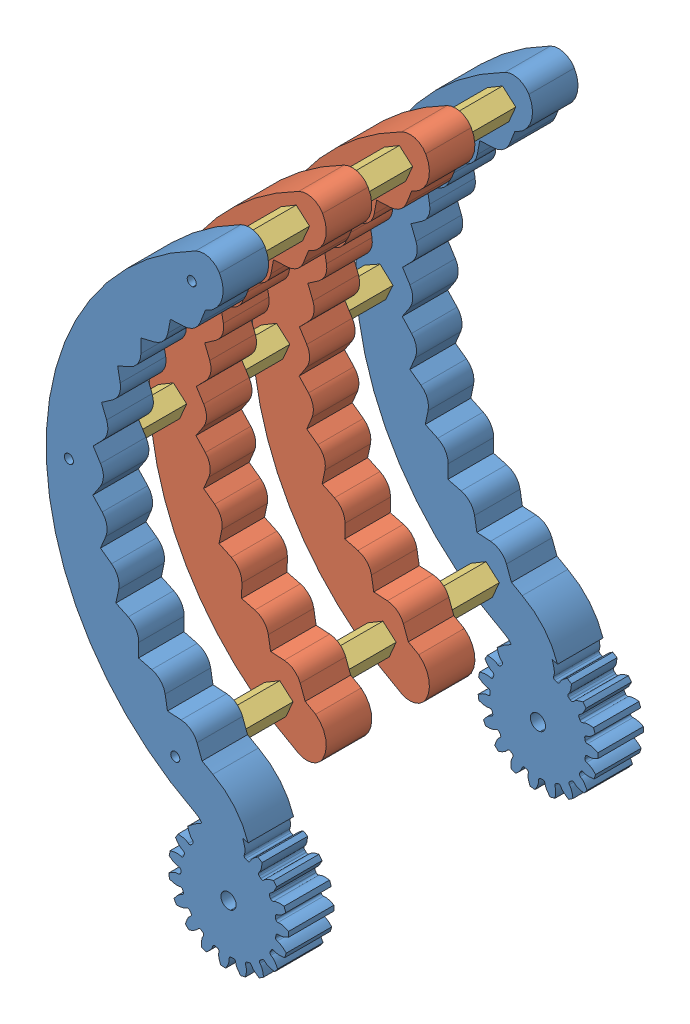
SolidWorks assembly 装配体_右爪子, configuration Default. Lengths in mm.
Overall size (79.93 200.48 117).
13 component instances, 3 part files, 27 mates.
Components (placement in the parent):
- 1_2.右爪子表面_打印两个-1: 1_2.右爪子表面_打印两个 [Varsayılan] at origin size (79.93 200.48 15)
- 1_3.爪子中间_打印四个-1: 1_3.爪子中间_打印四个 [Varsayılan] at (-2.9763 8.2953 -34) size (58.35 161.77 15)
- 2.铜柱连接件-1: 2.铜柱连接件 [Varsayılan] at (-63.7872 8.2778 -21.5) size (9.37 9.17 19)
- 2.铜柱连接件-2: 2.铜柱连接件 [Varsayılan] at (-23.2882 79.2861 -21.5) size (9.37 9.17 19)
- 2.铜柱连接件-3: 2.铜柱连接件 [Varsayılan] at (-23.2882 79.2861 -55.5) size (9.37 9.17 19)
- 2.铜柱连接件-4: 2.铜柱连接件 [Varsayılan] at (-28.7173 -59.225 -21.5) size (9.37 9.17 19)
- 2.铜柱连接件-5: 2.铜柱连接件 [Varsayılan] at (-28.7173 -59.225 -55.5) size (9.37 9.17 19)
- 2.铜柱连接件-6: 2.铜柱连接件 [Varsayılan] at (-23.2882 79.2861 -89.5) size (9.37 9.17 19)
- 2.铜柱连接件-7: 2.铜柱连接件 [Varsayılan] at (-28.7173 -59.225 -89.5) size (9.37 9.17 19)
- 2.铜柱连接件-8: 2.铜柱连接件 [Varsayılan] at (-63.7872 8.2778 -55.5) size (9.37 9.17 19)
- 2.铜柱连接件-9: 2.铜柱连接件 [Varsayılan] at (-63.7872 8.2778 -70.5) x (-0.498458 -0.866914 0) z (0 0 -1) size (9.37 9.17 19)
- 1_3.爪子中间_打印四个-2: 1_3.爪子中间_打印四个 [Varsayılan] at (-2.9763 8.2953 -68) size (58.35 161.77 15)
- 1_2.右爪子表面_打印两个-2: 1_2.右爪子表面_打印两个 [Varsayılan] at (0 0 -102) size (79.93 200.48 15)
Mates (geometry in assembly coordinates):
- 重合1: coincident anti-aligned: plane of 1_2.右爪子表面_打印两个-1 through (-26.0891 71.0659 -2.5) normal (0 0 -1); plane of 2.铜柱连接件-2 through (-23.2882 79.2861 -2.5) normal (0 0 1)
- 同心1: concentric aligned: cylinder of 1_2.右爪子表面_打印两个-1 through (-23.2882 79.2861 -1) axis (0 0 -1) radius 1.5; cylinder of 2.铜柱连接件-2 through (-23.2882 79.2861 -2.5) axis (0 0 -1) radius 2.5
- 重合2: coincident anti-aligned: plane of 1_2.右爪子表面_打印两个-1 through (-26.0891 71.0659 -2.5) normal (0 0 -1); plane of 2.铜柱连接件-1 through (-63.7872 8.2778 -2.5) normal (0 0 1)
- 同心2: concentric aligned: cylinder of 1_2.右爪子表面_打印两个-1 through (-63.7872 8.2778 -1) axis (0 0 -1) radius 1.5; cylinder of 2.铜柱连接件-1 through (-63.7872 8.2778 -2.5) axis (0 0 -1) radius 2.5
- 重合3: coincident anti-aligned: plane of 1_2.右爪子表面_打印两个-1 through (-26.0891 71.0659 -2.5) normal (0 0 -1); plane of 2.铜柱连接件-4 through (-28.7173 -59.225 -2.5) normal (0 0 1)
- 同心3: concentric aligned: circle of 1_2.右爪子表面_打印两个-1; circle of 2.铜柱连接件-4
- 重合4: coincident anti-aligned: plane of 1_3.爪子中间_打印四个-1 through (-26.0891 71.0659 -21.5) normal (0 0 1); plane of 2.铜柱连接件-2 through (-23.2882 79.2861 -21.5) normal (0 0 -1)
- 同心4: concentric aligned: cylinder of 1_3.爪子中间_打印四个-1 through (-23.2882 79.2861 -35) axis (0 0 -1) radius 1.5; cylinder of 2.铜柱连接件-2 through (-23.2882 79.2861 -2.5) axis (0 0 -1) radius 2.5
- 同心5: concentric aligned: cylinder of 1_3.爪子中间_打印四个-1 through (-63.7872 8.2778 -35) axis (0 0 -1) radius 1.5; cylinder of 2.铜柱连接件-1 through (-63.7872 8.2778 -2.5) axis (0 0 -1) radius 2.5
- 重合5: coincident anti-aligned: plane of 1_3.爪子中间_打印四个-1 through (-26.0891 71.0659 -36.5) normal (0 0 -1); circle of 2.铜柱连接件-3
- 同心6: concentric aligned: circle of 1_3.爪子中间_打印四个-1; circle of 2.铜柱连接件-3
- 重合6: coincident anti-aligned: plane of 1_3.爪子中间_打印四个-1 through (-26.0891 71.0659 -36.5) normal (0 0 -1); plane of 2.铜柱连接件-8 through (-63.7872 8.2778 -36.5) normal (0 0 1)
- 同心7: concentric aligned: circle of 1_3.爪子中间_打印四个-1; circle of 2.铜柱连接件-8
- 重合7: coincident anti-aligned: plane of 1_3.爪子中间_打印四个-1 through (-26.0891 71.0659 -36.5) normal (0 0 -1); plane of 2.铜柱连接件-5 through (-28.7173 -59.225 -36.5) normal (0 0 1)
- 同心8: concentric anti-aligned: cylinder of 1_3.爪子中间_打印四个-1 through (-28.7173 -59.225 -35) axis (0 0 -1) radius 1.5; circle of 2.铜柱连接件-5
- 重合8: coincident anti-aligned: plane of 2.铜柱连接件-3 through (-23.2882 79.2861 -55.5) normal (0 0 -1); plane of 1_3.爪子中间_打印四个-2 through (-26.0891 71.0659 -55.5) normal (0 0 1)
- 同心9: concentric anti-aligned: cylinder of 2.铜柱连接件-3 through (-23.2882 79.2861 -36.5) axis (0 0 -1) radius 2.5; circle of 1_3.爪子中间_打印四个-2
- 同心10: concentric aligned: cylinder of 2.铜柱连接件-8 through (-63.7872 8.2778 -36.5) axis (0 0 -1) radius 2.5; cylinder of 1_3.爪子中间_打印四个-2 through (-63.7872 8.2778 -69) axis (0 0 -1) radius 1.5
- 重合9: coincident aligned: plane of 2.铜柱连接件-6 through (-23.2882 79.2861 -70.5) normal (0 0 1); circle of 1_3.爪子中间_打印四个-2
- 同心11: concentric aligned: circle of 2.铜柱连接件-6; circle of 1_3.爪子中间_打印四个-2
- 重合11: coincident anti-aligned: plane of 2.铜柱连接件-9 through (-63.7872 8.2778 -70.5) normal (0 0 1); plane of 1_3.爪子中间_打印四个-2 through (-26.0891 71.0659 -70.5) normal (0 0 -1)
- 同心12: concentric anti-aligned: circle of 2.铜柱连接件-9; circle of 1_3.爪子中间_打印四个-2
- 重合12: coincident anti-aligned: plane of 2.铜柱连接件-7 through (-28.7173 -59.225 -70.5) normal (0 0 1); plane of 1_3.爪子中间_打印四个-2 through (-26.0891 71.0659 -70.5) normal (0 0 -1)
- 同心13: concentric aligned: cylinder of 2.铜柱连接件-7 through (-28.7173 -59.225 -70.5) axis (0 0 -1) radius 2.5; cylinder of 1_3.爪子中间_打印四个-2 through (-28.7173 -59.225 -69) axis (0 0 -1) radius 1.5
- 重合13: coincident anti-aligned: plane of 2.铜柱连接件-6 through (-23.2882 79.2861 -89.5) normal (0 0 -1); plane of 1_2.右爪子表面_打印两个-2 through (-26.0891 71.0659 -89.5) normal (0 0 1)
- 同心14: concentric aligned: cylinder of 2.铜柱连接件-6 through (-23.2882 79.2861 -70.5) axis (0 0 -1) radius 2.5; cylinder of 1_2.右爪子表面_打印两个-2 through (-23.2882 79.2861 -103) axis (0 0 -1) radius 1.5
- 同心15: concentric anti-aligned: cylinder of 2.铜柱连接件-9 through (-63.7872 8.2778 -89.5) axis (0 0 1) radius 2.5; cylinder of 1_2.右爪子表面_打印两个-2 through (-63.7872 8.2778 -103) axis (0 0 -1) radius 1.5
